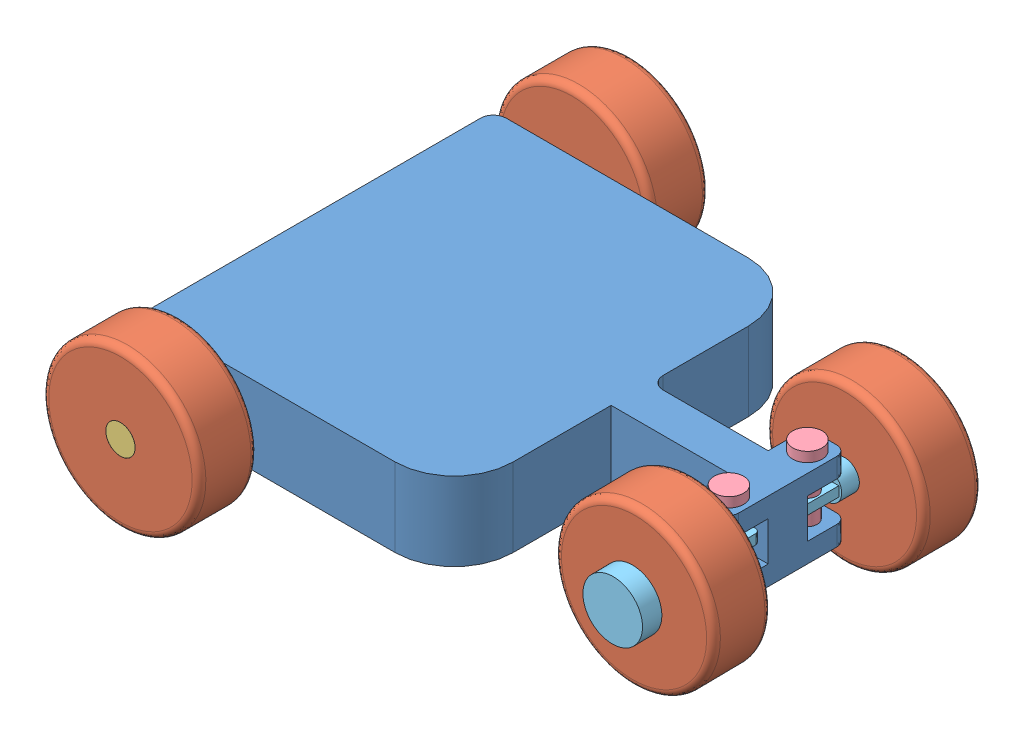
SolidWorks assembly mb_bot, configuration Default. Lengths in mm.
Overall size (801.01 307.12 660.4).
13 component instances, 5 part files, 11 mates.
Components (placement in the parent):
- Chassis-1: Chassis [Default] at origin size (609.6 101.6 457.2)
- rear_wheel-3: rear_wheel [Default] at (102.7476 0 137.1524) x (-0.477923 0.878379 0.006351) z (0.013289 0 0.999912) size (203.2 203.2 76.2)
- rear_axle-2: rear_axle [Default] at (-406.4 0 0) x (-0.970883 -0.239552 0) z (0 0 1) size (253.73 253.73 660.4)
  - rear_axle-1: rear_axle [Default] at origin size (38.1 38.1 660.4)
  - rear_wheel-3: rear_wheel [Default] at (0 0 292.1) x (0.991546 0.129754 0) z (0 0 1) size (203.2 203.2 76.2)
  - rear_wheel-4: rear_wheel [Default] at (0 0 -292.1) x (0.956311 0.29235 0) z (0 0 1) size (203.2 203.2 76.2)
- front_axle-1: front_axle [Default] at (101.6 57.15 50.8) x (0.811735 0 -0.584026) z (0 -1 0) size (164.35 189.37 114.3)
  - pin_for_front_wheel-1: pin_for_front_wheel [Default] at origin size (38.1 38.1 114.3)
  - front_wheel_axle-1: front_wheel_axle [Default] at (-80.0743 114.4736 57.15) x (-0.819424 -0.573187 0) z (0.573187 -0.819424 0) size (76.2 76.2 177.8)
- front_axle-2: front_axle [Default] at (101.6 57.15 -50.8) x (-0.816875 0 0.576815) z (0 -1 0) size (164.35 189.37 114.3)
  - pin_for_front_wheel-1: pin_for_front_wheel [Default] at origin size (38.1 38.1 114.3)
  - front_wheel_axle-1: front_wheel_axle [Default] at (-80.0743 114.4736 57.15) x (-0.819424 -0.573187 0) z (0.573187 -0.819424 0) size (76.2 76.2 177.8)
- rear_wheel-6: rear_wheel [Default] at (101.2171 0 -137.1592) x (-0.034041 0.99942 0.000151) z (-0.004433 0 -0.99999) size (203.2 203.2 76.2)
Mates (geometry in assembly coordinates):
- Concentric9: concentric anti-aligned: cylinder of Chassis-1 through (-406.4 0 -228.6) axis (0 0 1) radius 19.05; cylinder of rear_axle-2/rear_axle-1 through (-406.4 0 330.2) axis (0 0 -1) radius 19.05
- Concentric10: concentric aligned: cylinder of Chassis-1 through (101.6 -50.8 50.8) axis (0 1 0) radius 12.7; cylinder of front_axle-1/pin_for_front_wheel-1 through (101.6 -50.8 50.8) axis (0 1 0) radius 12.7
- Distance4: distance = 101.6 mm aligned: plane of front_axle-1/pin_for_front_wheel-1 through (101.6 50.8 50.8) normal (0 -1 0); plane of Chassis-1 through (-152.4 -50.8 -152.4) normal (0 -1 0)
- Concentric11: concentric anti-aligned: cylinder of rear_wheel-3 through (103.2539 0 175.249) axis (-0.013289 0 -0.999912) radius 19.05; cylinder of front_axle-1/front_wheel_axle-1 through (101.9375 0 76.1978) axis (0.013289 0 0.999912) radius 19.05
- Distance6: distance = 2.54 mm anti-aligned: plane of rear_wheel-3 through (103.2539 0 175.249) normal (0.013289 0 0.999912); plane of front_axle-1/front_wheel_axle-1 through (103.2876 0 177.7888) normal (-0.013289 0 -0.999912)
- Concentric12: concentric anti-aligned: cylinder of front_axle-2/front_wheel_axle-1 through (101.4874 0 -76.1998) axis (-0.004433 0 -0.99999) radius 19.05; cylinder of rear_wheel-6 through (101.0482 0 -175.2588) axis (0.004433 0 0.99999) radius 19.05
- Distance7: distance = 2.54 mm anti-aligned: plane of front_axle-2/front_wheel_axle-1 through (101.037 0 -177.7988) normal (0.004433 0 0.99999); plane of rear_wheel-6 through (101.0482 0 -175.2588) normal (-0.004433 0 -0.99999)
- Concentric13: concentric aligned: cylinder of Chassis-1 through (101.6 -50.8 -50.8) axis (0 1 0) radius 12.7; cylinder of front_axle-2/pin_for_front_wheel-1 through (101.6 -50.8 -50.8) axis (0 1 0) radius 12.7
- Distance5: distance = 101.6 mm aligned: plane of front_axle-2/pin_for_front_wheel-1 through (101.6 50.8 -50.8) normal (0 -1 0); plane of Chassis-1 through (-152.4 -50.8 -152.4) normal (0 -1 0)
- Distance1: distance = 101.6 mm aligned: plane of Chassis-1 through (-152.4 50.8 -228.6) normal (0 0 -1); plane of rear_axle-2/rear_wheel-4 through (-406.4 0 -330.2) normal (0 0 -1)
- Coincident1: coordinate: unknown of Chassis-1
